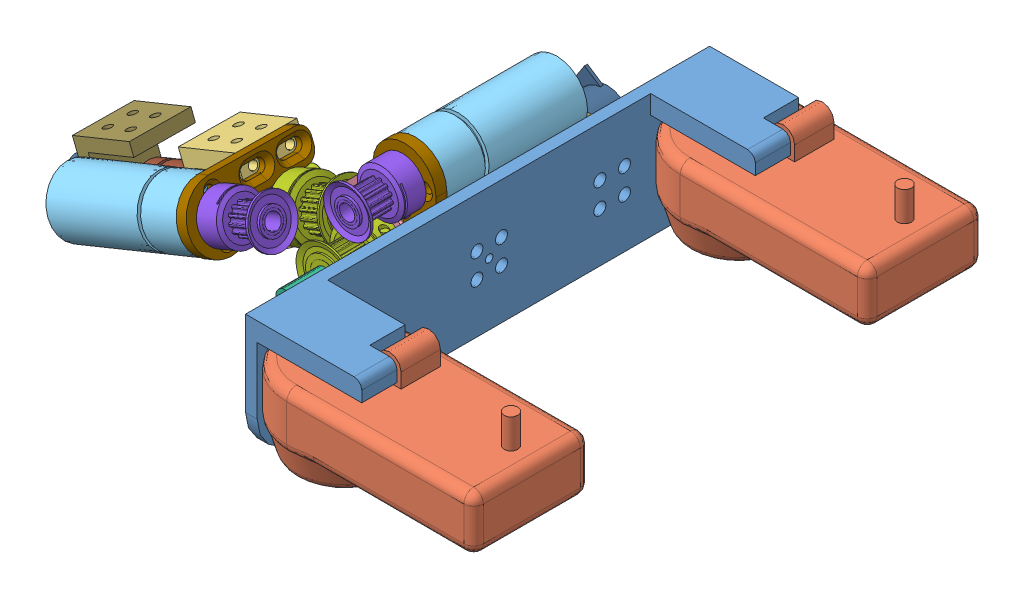
SolidWorks assembly VISION_HEAD_ASM, configuration Default. Lengths in mm.
Overall size (359.38 123.05 131.7).
31 component instances, 15 part files, 15 mates.
Components (placement in the parent):
- Head-Camera-Support-V2-1: Head-Camera-Support-V2 [Default] at origin size (30 32 119.8)
- LOGITECH_USB_CAM-1: LOGITECH_USB_CAM [Default] at (-11.43 -3.81 7.9) x (0 0 -1) z (0 -1 0) size (30.1 63.31 29.21)
- LOGITECH_USB_CAM-2: LOGITECH_USB_CAM [Default] at (-11.43 -3.81 -93.7) x (0 0 -1) z (0 -1 0) size (30.1 63.31 29.21)
- head-pin-joint-2: head-pin-joint [Default] at (-28 -14 -42.9) x (0 1 0) z (0 0 1) size (34.59 24.97 83.16)
  - n05-headyoke-1: n05-headyoke [Default] at origin size (15.88 21.91 15.88)
  - p1875bearing-57155K319-MCM-1: p1875bearing-57155K319-MCM [Default] at (0 13.97 5.5499) x (0 0 -1) z (0 -1 0) size (3.17 11.18 11.18)
  - p1875bearing-57155K319-MCM-2: p1875bearing-57155K319-MCM [Default] at (0 13.97 -5.5499) x (0 0 1) z (0 -1 0) size (3.17 11.18 11.18)
  - MAXON-AMAX16-110049-110323-1: MAXON-AMAX16-110049-110323 [Default] at (17.4625 8.128 -28.5125) x (0 0 -1) z (1 0 0) size (48.2 16 16)
  - n06-p1875shaft-1: n06-p1875shaft [Default] at (0 13.97 -15.0749) size (4.76 4.76 50.8)
  - a_6d16-016df2506-p1875bore-16teeth-1: a_6d16-016df2506-p1875bore-16teeth [Default] at (0 13.97 17.218) x (0.167713 -0.985836 0) z (0 0 -1) size (14.73 14.73 14.29)
  - a_6d16m012df6003-3mm-bored-to-4mm-1: a_6d16m012df6003-3mm-bored-to-4mm [Default] at (17.4625 8.128 17.2524) x (-0.948708 0.316155 0) z (0 0 -1) size (12.2 12.2 14.3)
  - a_6n16-015df1206-2: a_6n16-015df1206 [Default] at (-14.2838 6.954 15.9813) x (0.986257 0.164531 -0.015045) z (-0.021924 0.040076 -0.998956) size (14.1 14.1 11.13) (hidden)
  - n09-motor-holder-1: n09-motor-holder [Default] at (17.4625 8.128 7.9375) size (33.53 16.26 2.9)
  - POT-eti-sys-EUP125-1: POT-eti-sys-EUP125 [Default] at (0 13.97 -47.4345) x (0 0 -1) z (0.836462 -0.548026 0) size (30.58 15.39 13)
  - 000_helical-coupling-6208K53-MCM-1: 000_helical-coupling-6208K53-MCM [Default] at (0 13.97 -18.3769) size (12.7 12.7 19.05)
  - n10-potholder-1: n10-potholder [Default] at (0 0 -29.5148) size (15.88 21.91 15.88)
- head-pin-joint-3: head-pin-joint [Default] at (-90.0766 -18.4589 -43.0141) x (-0.003074 0.007569 0.999967) z (0.926512 0.376265 0) size (34.59 24.97 83.16)
  - n05-headyoke-1: n05-headyoke [Default] at origin size (15.88 21.91 15.88)
  - p1875bearing-57155K319-MCM-1: p1875bearing-57155K319-MCM [Default] at (0 13.97 5.5499) x (0 0 -1) z (0 -1 0) size (3.17 11.18 11.18)
  - p1875bearing-57155K319-MCM-2: p1875bearing-57155K319-MCM [Default] at (0 13.97 -5.5499) x (0 0 1) z (0 -1 0) size (3.17 11.18 11.18)
  - MAXON-AMAX16-110049-110323-1: MAXON-AMAX16-110049-110323 [Default] at (17.4625 8.128 -28.5125) x (0 0 -1) z (1 0 0) size (48.2 16 16)
  - n06-p1875shaft-1: n06-p1875shaft [Default] at (0 13.97 -15.0749) size (4.76 4.76 50.8)
  - a_6d16-016df2506-p1875bore-16teeth-1: a_6d16-016df2506-p1875bore-16teeth [Default] at (0 13.97 17.218) x (0.167713 -0.985836 0) z (0 0 -1) size (14.73 14.73 14.29)
  - a_6d16m012df6003-3mm-bored-to-4mm-1: a_6d16m012df6003-3mm-bored-to-4mm [Default] at (17.4625 8.128 17.2524) x (-0.948708 0.316155 0) z (0 0 -1) size (12.2 12.2 14.3)
  - a_6n16-015df1206-2: a_6n16-015df1206 [Default] at (-14.2838 6.954 15.9813) x (0.986257 0.164531 -0.015045) z (-0.021924 0.040076 -0.998956) size (14.1 14.1 11.13) (hidden)
  - n09-motor-holder-1: n09-motor-holder [Default] at (17.4625 8.128 7.9375) size (33.53 16.26 2.9)
  - POT-eti-sys-EUP125-1: POT-eti-sys-EUP125 [Default] at (0 13.97 -47.4345) x (0 0 -1) z (0.836462 -0.548026 0) size (30.58 15.39 13)
  - 000_helical-coupling-6208K53-MCM-1: 000_helical-coupling-6208K53-MCM [Default] at (0 13.97 -18.3769) size (12.7 12.7 19.05)
  - n10-potholder-1: n10-potholder [Default] at (0 0 -29.5148) size (15.88 21.91 15.88)
- n07-shaft-to-cams-1: n07-shaft-to-cams [Default] at (-41.97 -14 -38.1375) x (0.376265 -0.926512 0) z (0 0 -1) size (12.7 25.35 9.53)
- n08-neck-bar-long-1: n08-neck-bar-long [Default] at (-204.8557 -54.7916 -43.0919) x (-0.003074 0.007569 0.999967) z (0.926512 0.376265 0) size (15.88 9.53 254)
Mates (geometry in assembly coordinates):
- Concentric1: concentric aligned: cylinder of Head-Camera-Support-V2-1; cylinder of LOGITECH_USB_CAM-2
- Concentric2: concentric anti-aligned: cylinder of Head-Camera-Support-V2-1; cylinder of LOGITECH_USB_CAM-1
- Coincident1: coincident anti-aligned: plane of Head-Camera-Support-V2-1 through (0 0 7.9) normal (0 0 -1); plane of LOGITECH_USB_CAM-1 through (0 0 7.9) normal (0 0 1)
- Coincident2: coincident anti-aligned: plane of Head-Camera-Support-V2-1 through (0 0 -93.7) normal (0 0 -1); plane of LOGITECH_USB_CAM-2 through (0 0 -93.7) normal (0 0 1)
- Parallel1: parallel aligned: plane of Head-Camera-Support-V2-1 through (0 2 17) normal (0 1 0); plane of LOGITECH_USB_CAM-1 through (-11.43 -3.81 7.9) normal (0 1 0)
- Coincident4: coincident aligned: plane of LOGITECH_USB_CAM-1 through (-11.43 -3.81 7.9) normal (0 1 0); plane of LOGITECH_USB_CAM-2 through (-11.43 -3.81 -93.7) normal (0 1 0)
- Concentric5: concentric anti-aligned: cylinder of head-pin-joint-2/n06-p1875shaft-1; cylinder of n07-shaft-to-cams-1
- Distance1: distance = 0.3175 mm anti-aligned: plane of head-pin-joint-2/n05-headyoke-1 through (-32.064 -21.9375 -37.82) normal (0 0 -1); plane of n07-shaft-to-cams-1 through (-41.97 -14 -38.1375) normal (0 0 1)
- Concentric7: concentric aligned: cylinder of Head-Camera-Support-V2-1; cylinder of head-pin-joint-2/n05-headyoke-1
- Coincident7: coincident anti-aligned: plane of Head-Camera-Support-V2-1 through (-28 -30 -102.8) normal (-1 0 0); plane of head-pin-joint-2/n05-headyoke-1 through (-28 -6.0625 -34.9625) normal (1 0 0)
- Concentric8: concentric aligned: cylinder of Head-Camera-Support-V2-1; cylinder of head-pin-joint-2/n05-headyoke-1
- Concentric9: concentric aligned: cylinder of head-pin-joint-3/n06-p1875shaft-1; cylinder of n07-shaft-to-cams-1
- Coincident8: coincident anti-aligned: plane of head-pin-joint-3/n05-headyoke-1 through (-82.7468 -15.4123 -35.0769) normal (-0.376252 0.926481 -0.008169); plane of n08-neck-bar-long-1 through (-83.5805 -15.8908 -50.9514) normal (0.376252 -0.926481 0.008169)
- Concentric10: concentric anti-aligned: cylinder of head-pin-joint-3/n05-headyoke-1; cylinder of n08-neck-bar-long-1
- Concentric11: concentric anti-aligned: cylinder of head-pin-joint-3/n05-headyoke-1; cylinder of n08-neck-bar-long-1
